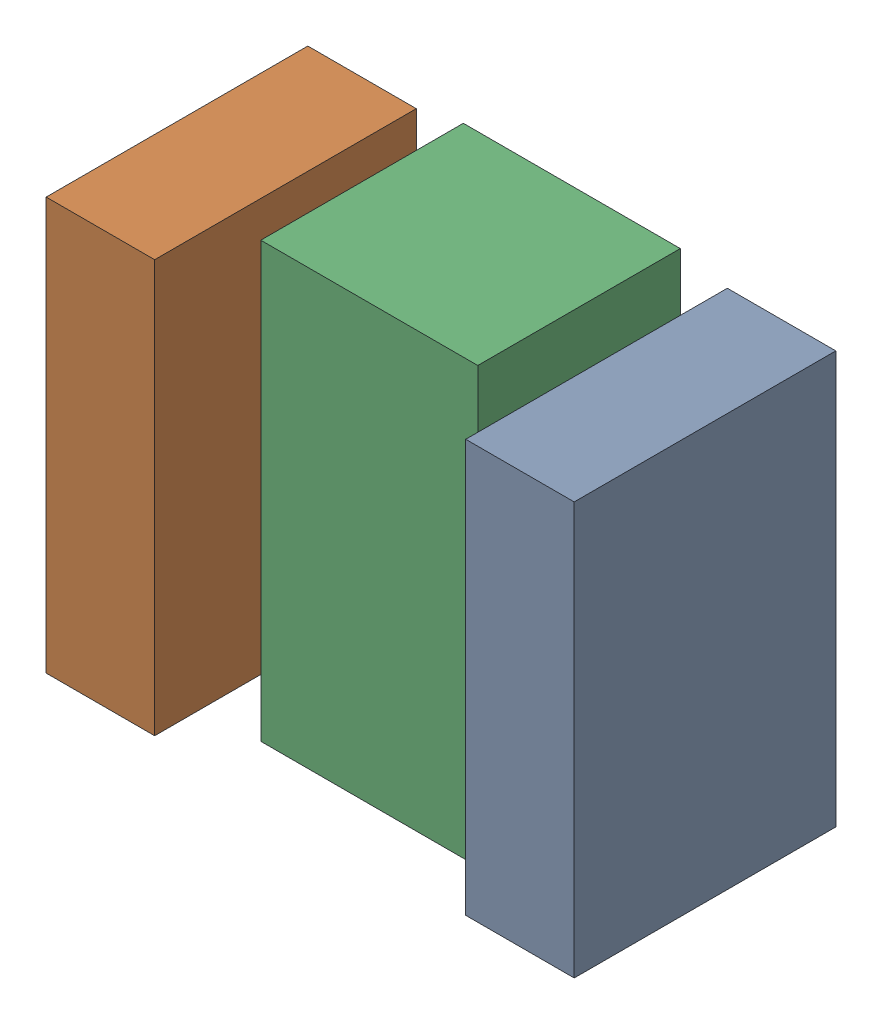
SolidWorks assembly C11_Motor_8Kanaloa_v2.0.0_Motor, configuration Default. Lengths in mm.
Overall size (3.65 3 1.81).
6 component instances, 2 part files, 0 mates.
Components (placement in the parent):
- 334788400-1: 334788400 [Default] at (121.604 135.763 0) size (0.75 2.85 1.81)
  - Extruded_5-1: Extruded_5 [Default] at origin size (0.75 2.85 1.81)
- 334788400-2: 334788400 [Default] at (118.704 135.763 0) size (0.75 2.85 1.81)
  - Extruded_5-1: Extruded_5 [Default] at origin size (0.75 2.85 1.81)
- 334788656-1: 334788656 [Default] at (120.154 135.763 0) size (1.5 3 1.4)
  - Extruded_1-1: Extruded_1 [Default] at origin size (1.5 3 1.4)
